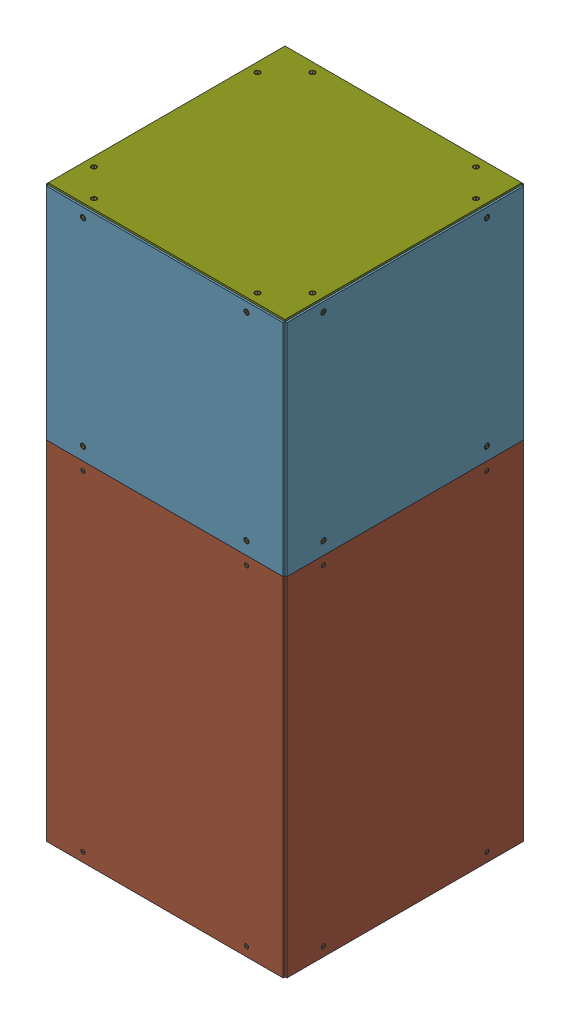
SolidWorks assembly SC.1.VIT1, configuration Showcase 570 x 570 x 870. Lengths in mm.
Overall size (656 1566.9 656).
215 component instances, 16 part files, 106 mates.
Components (placement in the parent):
- E1.CUBO-1: E1.CUBO [Estrutura 570 x 570 x 870] at (-428.8469 -414.8727 -259.3051) size (638 957.9 638)
  - E1.C-1: E1.C [E1.C1] at origin size (38 38 38)
  - E1.X-1: E1.X [E1.2] at (293.6116 -28.7561 -55.7313) x (0 1 0) z (0 0 1) size (30 570.2 30)
    - E1.X-15: E1.X [E1.2] at (43.1003 -291.3884 55.7313) size (30 570 30)
    - E1.CA-3: E1.CA [Default] at (43.7561 -291.3884 55.7313) x (0 1 0) z (0 0 1) size (14.2 10 10)
    - E1.CA-4: E1.CA [Default] at (43.7561 278.6116 55.7313) x (0 -1 0) z (0 0 1) size (14.2 10 10)
  - E1.X-10: E1.X [E1.2] at (-43.7561 70.7313 306.3884) x (1 0 0) z (0 -1 0) size (30 570.2 30)
    - E1.X-15: E1.X [E1.2] at (43.1003 -291.3884 55.7313) size (30 570 30)
    - E1.CA-3: E1.CA [Default] at (43.7561 -291.3884 55.7313) x (0 1 0) z (0 0 1) size (14.2 10 10)
    - E1.CA-4: E1.CA [Default] at (43.7561 278.6116 55.7313) x (0 -1 0) z (0 0 1) size (14.2 10 10)
  - socket button head screw_iso-2: socket button head screw_iso [ISO 7380 - M6 x 25 --- 25N] at (9.7 15 0) x (1 0 0) z (0 -0.833545 0.552452) size (28.3 10.5 10.5)
  - socket button head screw_iso-4: socket button head screw_iso [ISO 7380 - M6 x 25 --- 25N] at (0 15 9.7) x (0 0 1) z (-0.552452 -0.833545 0) size (28.3 10.5 10.5)
  - E1.C-2: E1.C [E1.C1] at (599.9999 30 -0.0001) x (1 0 0) z (0 0 -1) size (38 38 38)
  - socket button head screw_iso-5: socket button head screw_iso [ISO 7380 - M6 x 25 --- 25N] at (590.3 15 0) x (-1 0 0) z (0 0.833545 -0.552452) size (28.3 10.5 10.5)
  - E1.C-9: E1.C [E1.C1] at (0.0001 30 600.0001) x (-1 0 0) z (0 0 1) size (38 38 38)
  - socket button head screw_iso-6: socket button head screw_iso [ISO 7380 - M6 x 25 --- 25N] at (0 15 590.3) x (0 0 -1) z (0.552452 0.833545 0) size (28.3 10.5 10.5)
  - E1.PE-1: E1.PE [Default] at (9.0758 -8.3551 -4.8891) x (0.999731 0 0.023192) z (-0.023192 0 0.999731) size (24.13 30 20)
    - PÉ AJUSTÁVEL-1: PÉ AJUSTÁVEL [Default] at (-8.96 -15.5449 5.0983) size (20 30 20)
    - CLIP ROSCADO-1: CLIP ROSCADO [Default] at (-23.0861 4.4551 -0.1755) x (0.999731 0 -0.023192) z (0.023192 0 0.999731) size (19 10 11.2)
  - socket button head screw_iso-7: socket button head screw_iso [ISO 7380 - M6 x 25 --- 25N] at (590.3 15 600) x (-1 0 0) z (0 -0.833545 -0.552452) size (28.3 10.5 10.5)
  - E1.X-3: E1.X [E1.2] at (306.3884 -28.7561 655.7313) x (0 1 0) z (0 0 -1) size (30 570.2 30)
    - E1.X-15: E1.X [E1.2] at (43.1003 -291.3884 55.7313) size (30 570 30)
    - E1.CA-3: E1.CA [Default] at (43.7561 -291.3884 55.7313) x (0 1 0) z (0 0 1) size (14.2 10 10)
    - E1.CA-4: E1.CA [Default] at (43.7561 278.6116 55.7313) x (0 -1 0) z (0 0 1) size (14.2 10 10)
  - E1.X-11: E1.X [E1.2] at (643.7561 70.7313 293.6116) x (-1 0 0) z (0 -1 0) size (30 570.2 30)
    - E1.X-15: E1.X [E1.2] at (43.1003 -291.3884 55.7313) size (30 570 30)
    - E1.CA-3: E1.CA [Default] at (43.7561 -291.3884 55.7313) x (0 1 0) z (0 0 1) size (14.2 10 10)
    - E1.CA-4: E1.CA [Default] at (43.7561 278.6116 55.7313) x (0 -1 0) z (0 0 1) size (14.2 10 10)
  - E1.C-11: E1.C [E1.C1] at (600 0 600) x (-1 0 0) z (0 0 -1) size (38 38 38)
  - socket button head screw_iso-8: socket button head screw_iso [ISO 7380 - M6 x 25 --- 25N] at (600 15 9.7) x (0 0 1) z (-0.552452 0.833545 0) size (28.3 10.5 10.5)
  - socket button head screw_iso-9: socket button head screw_iso [ISO 7380 - M6 x 25 --- 25N] at (9.7 15 600) x (1 0 0) z (0 0.833545 0.552452) size (28.3 10.5 10.5)
  - socket button head screw_iso-10: socket button head screw_iso [ISO 7380 - M6 x 25 --- 25N] at (600 15 590.3) x (0 0 -1) z (0.552452 -0.833545 0) size (28.3 10.5 10.5)
  - E1.X-14: E1.X [E1.3] at (-43.7561 321.3884 -55.7313) size (30 870.2 30)
    - E1.X-15: E1.X [E1.3] at (43.1003 -291.3884 55.7313) size (30 870 30)
    - E1.CA-3: E1.CA [Default] at (43.7561 -291.3884 55.7313) x (0 1 0) z (0 0 1) size (14.2 10 10)
    - E1.CA-4: E1.CA [Default] at (43.7561 578.6116 55.7313) x (0 -1 0) z (0 0 1) size (14.2 10 10)
  - socket button head screw_iso-11: socket button head screw_iso [ISO 7380 - M6 x 25 --- 25N] at (590.3 915 600) x (-1 0 0) z (0 -0.833545 0.552452) size (28.3 10.5 10.5)
  - E1.X-6: E1.X [E1.2] at (306.3884 958.7561 544.2687) x (0 -1 0) z (0 0 1) size (30 570.2 30)
    - E1.X-15: E1.X [E1.2] at (43.1003 -291.3884 55.7313) size (30 570 30)
    - E1.CA-3: E1.CA [Default] at (43.7561 -291.3884 55.7313) x (0 1 0) z (0 0 1) size (14.2 10 10)
    - E1.CA-4: E1.CA [Default] at (43.7561 278.6116 55.7313) x (0 -1 0) z (0 0 1) size (14.2 10 10)
  - E1.X-12: E1.X [E1.2] at (643.7561 970.7313 293.6116) x (-1 0 0) z (0 -1 0) size (30 570.2 30)
    - E1.X-15: E1.X [E1.2] at (43.1003 -291.3884 55.7313) size (30 570 30)
    - E1.CA-3: E1.CA [Default] at (43.7561 -291.3884 55.7313) x (0 1 0) z (0 0 1) size (14.2 10 10)
    - E1.CA-4: E1.CA [Default] at (43.7561 278.6116 55.7313) x (0 -1 0) z (0 0 1) size (14.2 10 10)
  - E1.C-12: E1.C [E1.C1] at (599.9999 900 600.0001) size (38 38 38)
  - socket button head screw_iso-12: socket button head screw_iso [ISO 7380 - M6 x 25 --- 25N] at (600 915 9.7) x (0 0 1) z (0.552452 0.833545 0) size (28.3 10.5 10.5)
  - socket button head screw_iso-13: socket button head screw_iso [ISO 7380 - M6 x 25 --- 25N] at (9.7 915 600) x (1 0 0) z (0 0.833545 -0.552452) size (28.3 10.5 10.5)
  - socket button head screw_iso-14: socket button head screw_iso [ISO 7380 - M6 x 25 --- 25N] at (600 915 590.3) x (0 0 -1) z (-0.552452 -0.833545 0) size (28.3 10.5 10.5)
  - E1.C-10: E1.C [E1.C1] at (0 930 600) x (1 0 0) z (0 0 -1) size (38 38 38)
  - socket button head screw_iso-15: socket button head screw_iso [ISO 7380 - M6 x 25 --- 25N] at (0 915 590.3) x (0 0 -1) z (-0.552452 0.833545 0) size (28.3 10.5 10.5)
  - socket button head screw_iso-16: socket button head screw_iso [ISO 7380 - M6 x 25 --- 25N] at (0 915 9.7) x (0 0 1) z (0.552452 -0.833545 0) size (28.3 10.5 10.5)
  - socket button head screw_iso-17: socket button head screw_iso [ISO 7380 - M6 x 25 --- 25N] at (9.7 915 0) x (1 0 0) z (0 -0.833545 -0.552452) size (28.3 10.5 10.5)
  - E1.X-13: E1.X [E1.2] at (-43.7561 970.7313 306.3884) x (1 0 0) z (0 -1 0) size (30 570.2 30)
    - E1.X-15: E1.X [E1.2] at (43.1003 -291.3884 55.7313) size (30 570 30)
    - E1.CA-3: E1.CA [Default] at (43.7561 -291.3884 55.7313) x (0 1 0) z (0 0 1) size (14.2 10 10)
    - E1.CA-4: E1.CA [Default] at (43.7561 278.6116 55.7313) x (0 -1 0) z (0 0 1) size (14.2 10 10)
  - E1.X-9: E1.X [E1.2] at (293.6116 958.7561 55.7313) x (0 -1 0) z (0 0 -1) size (30 570.2 30)
    - E1.X-15: E1.X [E1.2] at (43.1003 -291.3884 55.7313) size (30 570 30)
    - E1.CA-3: E1.CA [Default] at (43.7561 -291.3884 55.7313) x (0 1 0) z (0 0 1) size (14.2 10 10)
    - E1.CA-4: E1.CA [Default] at (43.7561 278.6116 55.7313) x (0 -1 0) z (0 0 1) size (14.2 10 10)
  - E1.C-13: E1.C [E1.C1] at (0.0001 900 -0.0001) x (-1 0 0) z (0 0 -1) size (38 38 38)
  - E1.C-8: E1.C [E1.C1] at (600 930 0) x (-1 0 0) z (0 0 1) size (38 38 38)
  - socket button head screw_iso-18: socket button head screw_iso [ISO 7380 - M6 x 25 --- 25N] at (590.3 915 0) x (-1 0 0) z (0 0.833545 0.552452) size (28.3 10.5 10.5)
  - socket button head screw_iso-19: socket button head screw_iso [ISO 7380 - M6 x 25 --- 25N] at (0 24.7 0) x (0 1 0) z (-0.552452 0 0.833545) size (28.3 10.5 10.5)
  - socket button head screw_iso-20: socket button head screw_iso [ISO 7380 - M6 x 25 --- 25N] at (0 905.3 0) x (0 -1 0) z (0.981443 0 0.191756) size (28.3 10.5 10.5)
  - E1.X-16: E1.X [E1.3] at (-43.7561 321.3884 544.2687) size (30 870.2 30)
    - E1.X-15: E1.X [E1.3] at (43.1003 -291.3884 55.7313) size (30 870 30)
    - E1.CA-3: E1.CA [Default] at (43.7561 -291.3884 55.7313) x (0 1 0) z (0 0 1) size (14.2 10 10)
    - E1.CA-4: E1.CA [Default] at (43.7561 578.6116 55.7313) x (0 -1 0) z (0 0 1) size (14.2 10 10)
  - socket button head screw_iso-21: socket button head screw_iso [ISO 7380 - M6 x 25 --- 25N] at (0 905.3 600) x (0 -1 0) z (-0.981443 0 0.191756) size (28.3 10.5 10.5)
  - socket button head screw_iso-22: socket button head screw_iso [ISO 7380 - M6 x 25 --- 25N] at (0 24.7 600) x (0 1 0) z (0.552452 0 0.833545) size (28.3 10.5 10.5)
  - socket button head screw_iso-23: socket button head screw_iso [ISO 7380 - M6 x 25 --- 25N] at (600 24.7 600) x (0 1 0) z (0.552452 0 -0.833545) size (28.3 10.5 10.5)
  - socket button head screw_iso-24: socket button head screw_iso [ISO 7380 - M6 x 25 --- 25N] at (600 24.7 0) x (0 1 0) z (-0.552452 0 -0.833545) size (28.3 10.5 10.5)
  - socket button head screw_iso-25: socket button head screw_iso [ISO 7380 - M6 x 25 --- 25N] at (600 905.3 0) x (0 -1 0) z (0.981443 0 -0.191756) size (28.3 10.5 10.5)
  - E1.X-17: E1.X [E1.3] at (643.7561 321.3884 55.7313) x (-1 0 0) z (0 0 -1) size (30 870.2 30)
    - E1.X-15: E1.X [E1.3] at (43.1003 -291.3884 55.7313) size (30 870 30)
    - E1.CA-3: E1.CA [Default] at (43.7561 -291.3884 55.7313) x (0 1 0) z (0 0 1) size (14.2 10 10)
    - E1.CA-4: E1.CA [Default] at (43.7561 578.6116 55.7313) x (0 -1 0) z (0 0 1) size (14.2 10 10)
  - socket button head screw_iso-26: socket button head screw_iso [ISO 7380 - M6 x 25 --- 25N] at (600 905.3 600) x (0 -1 0) z (-0.981443 0 -0.191756) size (28.3 10.5 10.5)
  - E1.X-18: E1.X [E1.3] at (643.7561 321.3884 655.7313) x (-1 0 0) z (0 0 -1) size (30 870.2 30)
    - E1.X-15: E1.X [E1.3] at (43.1003 -291.3884 55.7313) size (30 870 30)
    - E1.CA-3: E1.CA [Default] at (43.7561 -291.3884 55.7313) x (0 1 0) z (0 0 1) size (14.2 10 10)
    - E1.CA-4: E1.CA [Default] at (43.7561 578.6116 55.7313) x (0 -1 0) z (0 0 1) size (14.2 10 10)
  - E1.PE-3: E1.PE [Default] at (590.9241 -8.3551 4.889) x (-0.999731 0 -0.023192) z (0.023192 0 -0.999731) size (24.13 30 20)
    - PÉ AJUSTÁVEL-1: PÉ AJUSTÁVEL [Default] at (-8.96 -15.5449 5.0983) size (20 30 20)
    - CLIP ROSCADO-1: CLIP ROSCADO [Default] at (-23.0861 4.4551 -0.1755) x (0.999731 0 -0.023192) z (0.023192 0 0.999731) size (19 10 11.2)
  - E1.PE-4: E1.PE [Default] at (590.9242 -8.3551 604.8891) x (-0.999731 0 -0.023192) z (0.023192 0 -0.999731) size (24.13 30 20)
    - PÉ AJUSTÁVEL-1: PÉ AJUSTÁVEL [Default] at (-8.96 -15.5449 5.0983) size (20 30 20)
    - CLIP ROSCADO-1: CLIP ROSCADO [Default] at (-23.0861 4.4551 -0.1755) x (0.999731 0 -0.023192) z (0.023192 0 0.999731) size (19 10 11.2)
  - E1.PE-5: E1.PE [Default] at (9.0759 -8.3551 595.111) x (0.999731 0 0.023192) z (-0.023192 0 0.999731) size (24.13 30 20)
    - PÉ AJUSTÁVEL-1: PÉ AJUSTÁVEL [Default] at (-8.96 -15.5449 5.0983) size (20 30 20)
    - CLIP ROSCADO-1: CLIP ROSCADO [Default] at (-23.0861 4.4551 -0.1755) x (0.999731 0 -0.023192) z (0.023192 0 0.999731) size (19 10 11.2)
- SC.1.G-1: SC.1.G [Default] at (-446.8469 500.1273 -182.3051) x (0 0 1) z (-1 0 0) size (70 79.5 2)
- SC.1.G-10: SC.1.G [Default] at (-446.8469 500.1273 263.6949) x (0 0 1) z (-1 0 0) size (70 79.5 2)
- E1.EP-1: E1.EP [Default] at (-448.8469 500.1273 263.6949) x (0 0.966847 0.255355) z (0 0.255355 -0.966847) size (10 5 10)
- E1.EP-9: E1.EP [Default] at (-448.8469 500.1273 -182.3051) x (0 0.966847 0.255355) z (0 0.255355 -0.966847) size (10 5 10)
- SC.1.G-12: SC.1.G [Default] at (94.1531 500.1273 -277.3051) x (-1 0 0) z (0 0 -1) size (70 79.5 2)
- E1.EP-11: E1.EP [Default] at (-351.8469 500.1273 -279.3051) x (-0.255355 0.966847 0) z (0.966847 0.255355 0) size (10 5 10)
- SC.1.G-14: SC.1.G [Default] at (-351.8469 500.1273 -277.3051) x (-1 0 0) z (0 0 -1) size (70 79.5 2)
- E1.EP-13: E1.EP [Default] at (94.1531 500.1273 -279.3051) x (-0.255355 0.966847 0) z (0.966847 0.255355 0) size (10 5 10)
- E1.EP-14: E1.EP [Default] at (94.1531 500.1273 360.6949) x (-0.255355 0.966847 0) z (-0.966847 -0.255355 0) size (10 5 10)
- SC.1.G-15: SC.1.G [Default] at (-351.8469 500.1273 356.6949) x (-1 0 0) z (0 0 -1) size (70 79.5 2)
- E1.EP-12: E1.EP [Default] at (-351.8469 500.1273 360.6949) x (-0.255355 0.966847 0) z (-0.966847 -0.255355 0) size (10 5 10)
- SC.1.G-13: SC.1.G [Default] at (94.1531 500.1273 356.6949) x (-1 0 0) z (0 0 -1) size (70 79.5 2)
- E1.EP-10: E1.EP [Default] at (191.1531 500.1273 -182.3051) x (0 0.966847 0.255355) z (0 -0.255355 0.966847) size (10 5 10)
- SC.1.G-11: SC.1.G [Default] at (187.1531 500.1273 263.6949) x (0 0 1) z (-1 0 0) size (70 79.5 2)
- SC.1.G-9: SC.1.G [Default] at (187.1531 500.1273 -182.3051) x (0 0 1) z (-1 0 0) size (70 79.5 2)
- E1.EP-8: E1.EP [Default] at (191.1531 500.1273 263.6949) x (0 0.966847 0.255355) z (0 -0.255355 0.966847) size (10 5 10)
- SC.1.AC2-1: SC.1.AC2 [Default] at (-451.8469 558.1273 -182.3051) size (10 13 13)
- SC.1.AC1-1: SC.1.AC1 [Default] at (-451.8469 558.1273 -182.3051) x (1 0 0) z (0 -0.384516 0.923118) size (5 13 13)
- SC.1.AC1-11: SC.1.AC1 [Default] at (94.1531 558.1273 -282.3051) x (0 0 1) z (-0.41724 -0.908796 0) size (5 13 13)
- SC.1.AC2-11: SC.1.AC2 [Default] at (94.1531 558.1273 -282.3051) x (0 0 1) z (-1 0 0) size (10 13 13)
- SC.1.AC2-13: SC.1.AC2 [Default] at (-451.8469 558.1273 263.6949) size (10 13 13)
- SC.1.AC1-13: SC.1.AC1 [Default] at (-451.8469 558.1273 263.6949) x (1 0 0) z (0 -0.384516 0.923118) size (5 13 13)
- SC.1.AC2-15: SC.1.AC2 [Default] at (-351.8469 558.1273 -282.3051) x (0 0 1) z (-1 0 0) size (10 13 13)
- SC.1.AC1-15: SC.1.AC1 [Default] at (-351.8469 558.1273 -282.3051) x (0 0 1) z (-0.923118 -0.384516 0) size (5 13 13)
- SC.1.AC2-16: SC.1.AC2 [Default] at (-351.8469 558.1273 363.6949) x (0 0 -1) z (1 0 0) size (10 13 13)
- SC.1.AC1-16: SC.1.AC1 [Default] at (-351.8469 558.1273 363.6949) x (0 0 -1) z (0.923118 0.384516 0) size (5 13 13)
- SC.1.AC2-12: SC.1.AC2 [Default] at (94.1531 558.1273 363.6949) x (0 0 -1) z (1 0 0) size (10 13 13)
- SC.1.AC1-12: SC.1.AC1 [Default] at (94.1531 558.1273 363.6949) x (0 0 -1) z (0.41724 0.908796 0) size (5 13 13)
- SC.1.AC2-10: SC.1.AC2 [Default] at (194.1531 558.1273 -182.3051) x (-1 0 0) z (0 0 -1) size (10 13 13)
- SC.1.AC1-10: SC.1.AC1 [Default] at (194.1531 558.1273 -182.3051) x (-1 0 0) z (0 0.384516 -0.923118) size (5 13 13)
- SC.1.AC2-14: SC.1.AC2 [Default] at (194.1531 558.1273 263.6949) x (-1 0 0) z (0 0 -1) size (10 13 13)
- SC.1.AC1-14: SC.1.AC1 [Default] at (194.1531 558.1273 263.6949) x (-1 0 0) z (0 0.384516 -0.923118) size (5 13 13)
- SC.1.RL-1: SC.1.RL [Lateral 953 x 646] at (-448.8469 51.6273 40.6949) x (0 0 1) z (-1 0 0) size (646 953 8)
- SC.1.RL-6: SC.1.RL [Lateral 953 x 646] at (-128.8469 51.6273 -279.3051) x (-1 0 0) z (0 0 -1) size (646 953 8)
- socket countersunk head screw_iso-1: socket countersunk head screw_iso [ISO 10642 - M5 x 12 --- 12N] at (-456.8469 500.1273 263.6949) size (12 9.43 9.43)
- socket countersunk head screw_iso-3: socket countersunk head screw_iso [ISO 10642 - M5 x 12 --- 12N] at (-456.8469 500.1273 -182.3051) size (12 9.43 9.43)
- socket countersunk head screw_iso-4: socket countersunk head screw_iso [ISO 10642 - M5 x 12 --- 12N] at (-456.8469 -399.8727 -182.3051) size (12 9.43 9.43)
- socket countersunk head screw_iso-5: socket countersunk head screw_iso [ISO 10642 - M5 x 12 --- 12N] at (-456.8469 -399.8727 263.6949) size (12 9.43 9.43)
- socket countersunk head screw_iso-6: socket countersunk head screw_iso [ISO 10642 - M5 x 12 --- 12N] at (-351.8469 -399.8727 -287.3051) x (0 0 1) z (-1 0 0) size (12 9.43 9.43)
- socket countersunk head screw_iso-7: socket countersunk head screw_iso [ISO 10642 - M5 x 12 --- 12N] at (94.1531 -399.8727 -287.3051) x (0 0 1) z (-1 0 0) size (12 9.43 9.43)
- socket countersunk head screw_iso-8: socket countersunk head screw_iso [ISO 10642 - M5 x 12 --- 12N] at (94.1531 500.1273 -287.3051) x (0 0 1) z (-1 0 0) size (12 9.43 9.43)
- socket countersunk head screw_iso-9: socket countersunk head screw_iso [ISO 10642 - M5 x 12 --- 12N] at (-351.8469 500.1273 -287.3051) x (0 0 1) z (-1 0 0) size (12 9.43 9.43)
- socket countersunk head screw_iso-10: socket countersunk head screw_iso [ISO 10642 - M5 x 16 --- 16N] at (-351.8469 558.1273 -287.3051) x (0 0 1) z (-1 0 0) size (16 9.43 9.43)
- socket countersunk head screw_iso-11: socket countersunk head screw_iso [ISO 10642 - M5 x 16 --- 16N] at (94.1531 558.1273 -287.3051) x (0 0 1) z (-1 0 0) size (16 9.43 9.43)
- socket countersunk head screw_iso-12: socket countersunk head screw_iso [ISO 10642 - M5 x 16 --- 16N] at (-456.8469 558.1273 -182.3051) size (16 9.43 9.43)
- socket countersunk head screw_iso-13: socket countersunk head screw_iso [ISO 10642 - M5 x 16 --- 16N] at (-456.8469 558.1273 263.6949) size (16 9.43 9.43)
- socket countersunk head screw_iso-14: socket countersunk head screw_iso [ISO 10642 - M5 x 16 --- 16N] at (-351.8469 558.1273 368.6949) x (0 0 -1) z (1 0 0) size (16 9.43 9.43)
- socket countersunk head screw_iso-15: socket countersunk head screw_iso [ISO 10642 - M5 x 16 --- 16N] at (94.1531 558.1273 368.6949) x (0 0 -1) z (1 0 0) size (16 9.43 9.43)
- SC.1.RL-7: SC.1.RL [Lateral 953 x 646] at (-128.8469 51.6273 360.6949) size (646 953 8)
- socket countersunk head screw_iso-16: socket countersunk head screw_iso [ISO 10642 - M5 x 12 --- 12N] at (94.1531 500.1273 368.6949) x (0 0 -1) z (1 0 0) size (12 9.43 9.43)
- socket countersunk head screw_iso-17: socket countersunk head screw_iso [ISO 10642 - M5 x 12 --- 12N] at (-351.8469 500.1273 368.6949) x (0 0 -1) z (1 0 0) size (12 9.43 9.43)
- socket countersunk head screw_iso-18: socket countersunk head screw_iso [ISO 10642 - M5 x 12 --- 12N] at (-351.8469 -399.8727 368.6949) x (0 0 -1) z (1 0 0) size (12 9.43 9.43)
- socket countersunk head screw_iso-19: socket countersunk head screw_iso [ISO 10642 - M5 x 12 --- 12N] at (94.1531 -399.8727 368.6949) x (0 0 -1) z (1 0 0) size (12 9.43 9.43)
- socket countersunk head screw_iso-20: socket countersunk head screw_iso [ISO 10642 - M5 x 16 --- 16N] at (199.1531 558.1273 -182.3051) x (-1 0 0) z (0 0 -1) size (16 9.43 9.43)
- socket countersunk head screw_iso-21: socket countersunk head screw_iso [ISO 10642 - M5 x 12 --- 12N] at (199.1531 500.1273 -182.3051) x (-1 0 0) z (0 0 -1) size (12 9.43 9.43)
- SC.1.RL-5: SC.1.RL [Lateral 953 x 646] at (191.1531 51.6273 40.6949) x (0 0 -1) z (1 0 0) size (646 953 8)
- socket countersunk head screw_iso-22: socket countersunk head screw_iso [ISO 10642 - M5 x 16 --- 16N] at (199.1531 558.1273 263.6949) x (-1 0 0) z (0 0 -1) size (16 9.43 9.43)
- socket countersunk head screw_iso-23: socket countersunk head screw_iso [ISO 10642 - M5 x 12 --- 12N] at (199.1531 500.1273 263.6949) x (-1 0 0) z (0 0 -1) size (12 9.43 9.43)
- socket countersunk head screw_iso-24: socket countersunk head screw_iso [ISO 10642 - M5 x 12 --- 12N] at (199.1531 -399.8727 263.6949) x (-1 0 0) z (0 0 -1) size (12 9.43 9.43)
- socket countersunk head screw_iso-25: socket countersunk head screw_iso [ISO 10642 - M5 x 12 --- 12N] at (199.1531 -399.8727 -182.3051) x (-1 0 0) z (0 0 -1) size (12 9.43 9.43)
- SC.1.RT-1: SC.1.RT [Topo 639 x 639] at (-128.8469 520.1273 40.6949) size (639 8 639)
- SC.1.VL-1: SC.1.VL [Lateral 646 x 600] at (-451.8469 823.1273 40.6949) x (0 0 1) z (-1 0 0) size (646 600 5)
- SC.1.VL-4: SC.1.VL [Lateral 646 x 600] at (-128.8469 823.1273 -282.3051) x (-1 0 0) z (0 0 -1) size (646 600 5)
- SC.1.L-1: SC.1.L [Default] at (-433.5969 1104.8773 -188.8051) size (26.5 26.5 13)
- SC.1.AC2-17: SC.1.AC2 [Default] at (-451.8469 1098.1273 -182.3051) size (10 13 13)
- SC.1.AC1-17: SC.1.AC1 [Default] at (-451.8469 1098.1273 -182.3051) size (5 13 13)
- SC.1.AC2-23: SC.1.AC2 [Default] at (-426.8469 1123.1273 -182.3051) x (0 -1 0) z (0 0 1) size (10 13 13)
- SC.1.AC1-24: SC.1.AC1 [Default] at (-426.8469 1123.1273 -182.3051) x (0 -1 0) z (0 0 1) size (5 13 13)
- socket countersunk head screw_iso-26: socket countersunk head screw_iso [ISO 10642 - M5 x 16 --- 16N] at (-456.8469 1098.1273 -182.3051) size (16 9.43 9.43)
- socket countersunk head screw_iso-27: socket countersunk head screw_iso [ISO 10642 - M5 x 16 --- 16N] at (-426.8469 1128.1273 -182.3051) x (0 -1 0) z (0 0 1) size (16 9.43 9.43)
- SC.1.L-2: SC.1.L [Default] at (-433.5969 1104.8773 257.1949) size (26.5 26.5 13)
- SC.1.AC2-18: SC.1.AC2 [Default] at (-451.8469 1098.1273 263.6949) size (10 13 13)
- SC.1.AC1-18: SC.1.AC1 [Default] at (-451.8469 1098.1273 263.6949) size (5 13 13)
- SC.1.AC2-24: SC.1.AC2 [Default] at (-426.8469 1123.1273 263.6949) x (0 -1 0) z (0 0 1) size (10 13 13)
- SC.1.AC1-25: SC.1.AC1 [Default] at (-426.8469 1123.1273 263.6949) x (0 -1 0) z (0 0 1) size (5 13 13)
- socket countersunk head screw_iso-28: socket countersunk head screw_iso [ISO 10642 - M5 x 16 --- 16N] at (-456.8469 1098.1273 263.6949) size (16 9.43 9.43)
- socket countersunk head screw_iso-29: socket countersunk head screw_iso [ISO 10642 - M5 x 16 --- 16N] at (-426.8469 1128.1273 263.6949) x (0 -1 0) z (0 0 1) size (16 9.43 9.43)
- SC.1.L-7: SC.1.L [Default] at (-345.3469 1104.8773 -264.0551) x (0 0 1) z (-1 0 0) size (26.5 26.5 13)
- SC.1.AC2-27: SC.1.AC2 [Default] at (-351.8469 1098.1273 -282.3051) x (0 0 1) z (-1 0 0) size (10 13 13)
- SC.1.AC2-31: SC.1.AC2 [Default] at (-351.8469 1123.1273 -257.3051) x (0 -1 0) z (0 0 1) size (10 13 13)
- SC.1.AC1-28: SC.1.AC1 [Default] at (-351.8469 1123.1273 -257.3051) x (0 -1 0) z (0 0 1) size (5 13 13)
- socket countersunk head screw_iso-30: socket countersunk head screw_iso [ISO 10642 - M5 x 16 --- 16N] at (-351.8469 1098.1273 -287.3051) x (0 0 1) z (-1 0 0) size (16 9.43 9.43)
- socket countersunk head screw_iso-31: socket countersunk head screw_iso [ISO 10642 - M5 x 16 --- 16N] at (-351.8469 1128.1273 -257.3051) x (0 -1 0) z (0 0 1) size (16 9.43 9.43)
- SC.1.AC1-32: SC.1.AC1 [Default] at (-351.8469 1098.1273 -282.3051) x (0 0 1) z (-1 0 0) size (5 13 13)
- socket countersunk head screw_iso-32: socket countersunk head screw_iso [ISO 10642 - M5 x 16 --- 16N] at (94.1531 1128.1273 -257.3051) x (0 -1 0) z (0 0 -1) size (16 9.43 9.43)
- SC.1.AC1-29: SC.1.AC1 [Default] at (94.1531 1123.1273 -257.3051) x (0 -1 0) z (0 0 -1) size (5 13 13)
- SC.1.AC2-32: SC.1.AC2 [Default] at (94.1531 1123.1273 -257.3051) x (0 -1 0) z (0 0 -1) size (10 13 13)
- SC.1.L-8: SC.1.L [Default] at (100.6531 1104.8773 -264.0551) x (0 0 1) z (-1 0 0) size (26.5 26.5 13)
- SC.1.AC2-28: SC.1.AC2 [Default] at (94.1531 1098.1273 -282.3051) x (0 0 1) z (-1 0 0) size (10 13 13)
- socket countersunk head screw_iso-33: socket countersunk head screw_iso [ISO 10642 - M5 x 16 --- 16N] at (94.1531 1098.1273 -287.3051) x (0 0 1) z (-1 0 0) size (16 9.43 9.43)
- SC.1.AC1-33: SC.1.AC1 [Default] at (94.1531 1098.1273 -282.3051) x (0 0 1) z (-1 0 0) size (5 13 13)
- SC.1.AC1-21: SC.1.AC1 [Default] at (194.1531 1098.1273 263.6949) x (-1 0 0) z (0 0 -1) size (5 13 13)
- SC.1.AC2-25: SC.1.AC2 [Default] at (169.1531 1123.1273 263.6949) x (0 -1 0) z (0 0 -1) size (10 13 13)
- SC.1.L-5: SC.1.L [Default] at (175.9031 1104.8773 270.1949) x (-1 0 0) z (0 0 -1) size (26.5 26.5 13)
- socket countersunk head screw_iso-34: socket countersunk head screw_iso [ISO 10642 - M5 x 16 --- 16N] at (169.1531 1128.1273 263.6949) x (0 -1 0) z (0 0 -1) size (16 9.43 9.43)
- SC.1.AC2-21: SC.1.AC2 [Default] at (194.1531 1098.1273 263.6949) x (-1 0 0) z (0 0 -1) size (10 13 13)
- SC.1.AC1-26: SC.1.AC1 [Default] at (169.1531 1123.1273 263.6949) x (0 -1 0) z (0 0 -1) size (5 13 13)
- socket countersunk head screw_iso-35: socket countersunk head screw_iso [ISO 10642 - M5 x 16 --- 16N] at (199.1531 1098.1273 263.6949) x (-1 0 0) z (0 0 -1) size (16 9.43 9.43)
- SC.1.VL-3: SC.1.VL [Lateral 646 x 600] at (194.1531 823.1273 40.6949) x (0 0 -1) z (1 0 0) size (646 600 5)
- socket countersunk head screw_iso-36: socket countersunk head screw_iso [ISO 10642 - M5 x 16 --- 16N] at (169.1531 1128.1273 -182.3051) x (0 -1 0) z (0 0 -1) size (16 9.43 9.43)
- socket countersunk head screw_iso-37: socket countersunk head screw_iso [ISO 10642 - M5 x 16 --- 16N] at (199.1531 1098.1273 -182.3051) x (-1 0 0) z (0 0 -1) size (16 9.43 9.43)
- SC.1.AC1-23: SC.1.AC1 [Default] at (194.1531 1098.1273 -182.3051) x (-1 0 0) z (0 0 -1) size (5 13 13)
- SC.1.AC2-22: SC.1.AC2 [Default] at (194.1531 1098.1273 -182.3051) x (-1 0 0) z (0 0 -1) size (10 13 13)
- SC.1.L-6: SC.1.L [Default] at (175.9031 1104.8773 -175.8051) x (-1 0 0) z (0 0 -1) size (26.5 26.5 13)
- SC.1.AC1-27: SC.1.AC1 [Default] at (169.1531 1123.1273 -182.3051) x (0 -1 0) z (0 0 -1) size (5 13 13)
- SC.1.AC2-26: SC.1.AC2 [Default] at (169.1531 1123.1273 -182.3051) x (0 -1 0) z (0 0 -1) size (10 13 13)
- SC.1.AC1-30: SC.1.AC1 [Default] at (94.1531 1123.1273 338.6949) x (0 -1 0) z (0 0 -1) size (5 13 13)
- socket countersunk head screw_iso-38: socket countersunk head screw_iso [ISO 10642 - M5 x 16 --- 16N] at (-351.8469 1098.1273 368.6949) x (0 0 -1) z (1 0 0) size (16 9.43 9.43)
- SC.1.L-10: SC.1.L [Default] at (-358.3469 1104.8773 345.4449) x (0 0 -1) z (1 0 0) size (26.5 26.5 13)
- SC.1.AC2-30: SC.1.AC2 [Default] at (-351.8469 1098.1273 363.6949) x (0 0 -1) z (1 0 0) size (10 13 13)
- SC.1.AC1-34: SC.1.AC1 [Default] at (94.1531 1098.1273 363.6949) x (0 0 -1) z (1 0 0) size (5 13 13)
- SC.1.AC2-34: SC.1.AC2 [Default] at (-351.8469 1123.1273 338.6949) x (0 -1 0) z (0 0 1) size (10 13 13)
- SC.1.AC2-33: SC.1.AC2 [Default] at (94.1531 1123.1273 338.6949) x (0 -1 0) z (0 0 -1) size (10 13 13)
- SC.1.L-9: SC.1.L [Default] at (87.6531 1104.8773 345.4449) x (0 0 -1) z (1 0 0) size (26.5 26.5 13)
- SC.1.AC2-29: SC.1.AC2 [Default] at (94.1531 1098.1273 363.6949) x (0 0 -1) z (1 0 0) size (10 13 13)
- socket countersunk head screw_iso-39: socket countersunk head screw_iso [ISO 10642 - M5 x 16 --- 16N] at (94.1531 1128.1273 338.6949) x (0 -1 0) z (0 0 -1) size (16 9.43 9.43)
- SC.1.AC1-31: SC.1.AC1 [Default] at (-351.8469 1123.1273 338.6949) x (0 -1 0) z (0 0 1) size (5 13 13)
- socket countersunk head screw_iso-40: socket countersunk head screw_iso [ISO 10642 - M5 x 16 --- 16N] at (-351.8469 1128.1273 338.6949) x (0 -1 0) z (0 0 1) size (16 9.43 9.43)
- SC.1.AC1-35: SC.1.AC1 [Default] at (-351.8469 1098.1273 363.6949) x (0 0 -1) z (1 0 0) size (5 13 13)
- socket countersunk head screw_iso-41: socket countersunk head screw_iso [ISO 10642 - M5 x 16 --- 16N] at (94.1531 1098.1273 368.6949) x (0 0 -1) z (1 0 0) size (16 9.43 9.43)
- SC.1.VL-5: SC.1.VL [Lateral 646 x 600] at (-128.8469 823.1273 363.6949) size (646 600 5)
- SC.1.VT-1: SC.1.VT [Topo 646 x 646] at (-128.8469 1123.1273 40.6949) x (0 0 1) z (-1 0 0) size (646 5 646)
Mates (geometry in assembly coordinates):
- Distance1: distance = 1 mm anti-aligned: plane of SC.1.G-1 through (-444.8469 558.1273 -182.3051) normal (1 0 0); plane of E1.CUBO-1/E1.X-10/E1.X-15 through (-443.8469 -411.8727 325.6949) normal (-1 0 0)
- Coincident2: coincident anti-aligned: plane of E1.CUBO-1/E1.X-14/E1.X-15 through (-433.1469 485.1273 -274.1051) normal (0 1 0); plane of SC.1.G-1 through (-444.8469 485.1273 -212.3051) normal (0 -1 0)
- Distance2: distance = 27 mm aligned: plane of SC.1.G-1 through (-444.8469 515.1273 -217.3051) normal (0 0 -1); plane of E1.CUBO-1/E1.X-10/E1.X-15 through (-433.1469 -385.0727 -244.3051) normal (0 0 -1)
- Distance6: distance = 1 mm anti-aligned: plane of SC.1.G-10 through (-444.8469 558.1273 263.6949) normal (1 0 0); plane of E1.CUBO-1/E1.X-10/E1.X-15 through (-443.8469 -387.8727 325.6949) normal (-1 0 0)
- Coincident6: coincident anti-aligned: plane of E1.CUBO-1/E1.X-14/E1.X-15 through (-433.1469 485.1273 -274.1051) normal (0 1 0); plane of SC.1.G-10 through (-444.8469 485.1273 233.6949) normal (0 -1 0)
- Distance7: distance = 27 mm aligned: plane of SC.1.G-10 through (-444.8469 490.1273 298.6949) normal (0 0 1); plane of E1.CUBO-1/E1.X-10/E1.X-15 through (-433.1469 -385.0727 325.6949) normal (0 0 1)
- Coincident8: coincident anti-aligned: plane of E1.CUBO-1/E1.X-10/E1.X-15 through (-443.8469 -387.8727 325.6949) normal (-1 0 0); plane of E1.EP-1 through (-443.8469 500.1273 263.6949) normal (1 0 0)
- Concentric1: concentric aligned: cylinder of SC.1.G-10 through (-444.8469 500.1273 263.6949) axis (-1 0 0) radius 5.1; cylinder of E1.EP-1 through (-443.8469 500.1273 263.6949) axis (-1 0 0) radius 5
- Coincident9: coincident anti-aligned: plane of E1.CUBO-1/E1.X-10/E1.X-15 through (-443.8469 -387.8727 325.6949) normal (-1 0 0); plane of E1.EP-9 through (-443.8469 500.1273 -182.3051) normal (1 0 0)
- Concentric2: concentric aligned: cylinder of SC.1.G-1 through (-444.8469 500.1273 -182.3051) axis (-1 0 0) radius 5.1; cylinder of E1.EP-9 through (-443.8469 500.1273 -182.3051) axis (-1 0 0) radius 5
- Distance8: distance = 1 mm anti-aligned: plane of SC.1.G-12 through (94.1531 558.1273 -275.3051) normal (0 0 1); plane of E1.CUBO-1/E1.X-1/E1.X-15 through (-413.8469 -387.8727 -274.3051) normal (0 0 -1)
- Coincident10: coincident anti-aligned: plane of E1.CUBO-1/E1.X-14/E1.X-15 through (-433.1469 485.1273 -274.1051) normal (0 1 0); plane of SC.1.G-12 through (124.1531 485.1273 -275.3051) normal (0 -1 0)
- Distance9: distance = 27 mm aligned: plane of SC.1.G-12 through (129.1531 515.1273 -275.3051) normal (1 0 0); plane of E1.CUBO-1/E1.X-1/E1.X-15 through (156.1531 -404.1727 -274.1051) normal (1 0 0)
- Concentric6: concentric aligned: cylinder of E1.EP-11 through (-351.8469 500.1273 -274.3051) axis (0 0 -1) radius 5; cylinder of SC.1.G-14 through (-351.8469 500.1273 -275.3051) axis (0 0 -1) radius 5.1
- Distance10: distance = 1 mm anti-aligned: plane of SC.1.G-14 through (-351.8469 558.1273 -275.3051) normal (0 0 1); plane of E1.CUBO-1/E1.X-1/E1.X-15 through (-413.8469 -387.8727 -274.3051) normal (0 0 -1)
- Coincident11: coincident anti-aligned: plane of E1.CUBO-1/E1.X-14/E1.X-15 through (-433.1469 485.1273 -274.1051) normal (0 1 0); plane of SC.1.G-14 through (-321.8469 485.1273 -275.3051) normal (0 -1 0)
- Distance11: distance = 27 mm aligned: plane of SC.1.G-14 through (-386.8469 490.1273 -275.3051) normal (-1 0 0); plane of E1.CUBO-1/E1.X-1/E1.X-15 through (-413.8469 -404.1727 -274.1051) normal (-1 0 0)
- Coincident14: coincident anti-aligned: plane of E1.CUBO-1/E1.X-1/E1.X-15 through (-413.8469 -387.8727 -274.3051) normal (0 0 -1); plane of E1.EP-11 through (-351.8469 500.1273 -274.3051) normal (0 0 1)
- Coincident15: coincident anti-aligned: plane of E1.CUBO-1/E1.X-1/E1.X-15 through (-413.8469 -387.8727 -274.3051) normal (0 0 -1); plane of E1.EP-13 through (94.1531 500.1273 -274.3051) normal (0 0 1)
- Concentric7: concentric aligned: cylinder of SC.1.G-12 through (94.1531 500.1273 -275.3051) axis (0 0 -1) radius 5.1; cylinder of E1.EP-13 through (94.1531 500.1273 -274.3051) axis (0 0 -1) radius 5
- Concentric8: concentric aligned: cylinder of SC.1.G-1 through (-446.8469 558.1273 -182.3051) axis (-1 0 0) radius 2.1; cylinder of SC.1.AC2-1 through (-461.4266 558.1273 -182.3051) axis (-1 0 0) radius 4
- Coincident16: coincident anti-aligned: plane of SC.1.G-1 through (-446.8469 558.1273 -182.3051) normal (-1 0 0); plane of SC.1.AC2-1 through (-446.8469 562.1273 -182.3051) normal (1 0 0)
- Concentric9: concentric aligned: cylinder of SC.1.AC2-1 through (-461.4266 558.1273 -182.3051) axis (-1 0 0) radius 4; cylinder of SC.1.AC1-1 through (-446.8469 558.1273 -182.3051) axis (-1 0 0) radius 4
- Coincident17: coincident anti-aligned: plane of SC.1.G-1 through (-446.8469 558.1273 -182.3051) normal (-1 0 0); plane of SC.1.AC1-1 through (-446.8469 558.1273 -182.3051) normal (1 0 0)
- Concentric14: concentric aligned: cylinder of SC.1.AC1-11 through (94.1531 558.1273 -277.3051) axis (0 0 -1) radius 4; cylinder of SC.1.AC2-11 through (94.1531 558.1273 -291.8847) axis (0 0 -1) radius 4
- Concentric15: concentric aligned: cylinder of SC.1.G-12 through (94.1531 558.1273 -277.3051) axis (0 0 -1) radius 2.1; cylinder of SC.1.AC2-11 through (94.1531 558.1273 -291.8847) axis (0 0 -1) radius 4
- Coincident23: coincident anti-aligned: plane of SC.1.G-12 through (94.1531 558.1273 -277.3051) normal (0 0 -1); plane of SC.1.AC2-11 through (94.1531 562.1273 -277.3051) normal (0 0 1)
- Coincident26: coincident anti-aligned: plane of SC.1.G-12 through (94.1531 558.1273 -277.3051) normal (0 0 -1); plane of SC.1.AC1-11 through (94.1531 558.1273 -277.3051) normal (0 0 1)
- Concentric18: concentric aligned: cylinder of SC.1.AC2-13 through (-461.4266 558.1273 263.6949) axis (-1 0 0) radius 4; cylinder of SC.1.AC1-13 through (-446.8469 558.1273 263.6949) axis (-1 0 0) radius 4
- Concentric19: concentric aligned: cylinder of SC.1.G-10 through (-446.8469 558.1273 263.6949) axis (-1 0 0) radius 2.1; cylinder of SC.1.AC2-13 through (-461.4266 558.1273 263.6949) axis (-1 0 0) radius 4
- Coincident27: coincident anti-aligned: plane of SC.1.G-10 through (-446.8469 558.1273 263.6949) normal (-1 0 0); plane of SC.1.AC2-13 through (-446.8469 562.1273 263.6949) normal (1 0 0)
- Coincident28: coincident anti-aligned: plane of SC.1.G-10 through (-446.8469 558.1273 263.6949) normal (-1 0 0); plane of SC.1.AC1-13 through (-446.8469 558.1273 263.6949) normal (1 0 0)
- Concentric20: concentric aligned: cylinder of SC.1.AC2-15 through (-351.8469 558.1273 -291.8847) axis (0 0 -1) radius 4; cylinder of SC.1.AC1-15 through (-351.8469 558.1273 -277.3051) axis (0 0 -1) radius 4
- Concentric21: concentric aligned: cylinder of SC.1.G-14 through (-351.8469 558.1273 -277.3051) axis (0 0 -1) radius 2.1; cylinder of SC.1.AC2-15 through (-351.8469 558.1273 -291.8847) axis (0 0 -1) radius 4
- Coincident29: coincident anti-aligned: plane of SC.1.G-14 through (-351.8469 558.1273 -277.3051) normal (0 0 -1); plane of SC.1.AC2-15 through (-351.8469 562.1273 -277.3051) normal (0 0 1)
- Coincident30: coincident anti-aligned: plane of SC.1.G-14 through (-351.8469 558.1273 -277.3051) normal (0 0 -1); plane of SC.1.AC1-15 through (-351.8469 558.1273 -277.3051) normal (0 0 1)
- Coincident31: coincident anti-aligned: plane of E1.EP-9 through (-448.8469 500.1273 -182.3051) normal (-1 0 0); plane of SC.1.RL-1 through (-448.8469 51.6273 40.6949) normal (1 0 0)
- Distance12: distance = 8 mm aligned: plane of SC.1.RL-1 through (-456.8469 -424.8727 -282.3051) normal (0 0 -1); plane of E1.CUBO-1/E1.X-14/E1.X-15 through (-440.8469 485.1273 -274.3051) normal (0 0 -1)
- Distance15: distance = 10 mm aligned: plane of E1.CUBO-1/E1.X-10/E1.X-15 through (-440.8469 -414.8727 325.6949) normal (0 -1 0); plane of SC.1.RL-1 through (-456.8469 -424.8727 -282.3051) normal (0 -1 0)
- Coincident34: coincident anti-aligned: plane of E1.EP-13 through (94.1531 500.1273 -279.3051) normal (0 0 -1); plane of SC.1.RL-6 through (-128.8469 51.6273 -279.3051) normal (0 0 1)
- Distance13: distance = 8 mm aligned: plane of SC.1.RL-6 through (-451.8469 -424.8727 -287.3051) normal (-1 0 0); plane of E1.CUBO-1/E1.X-10/E1.X-15 through (-443.8469 -387.8727 325.6949) normal (-1 0 0)
- Distance14: distance = 10 mm aligned: plane of SC.1.RL-6 through (194.1531 -424.8727 -287.3051) normal (0 -1 0); plane of E1.CUBO-1/E1.X-1/E1.X-15 through (-413.8469 -414.8727 -271.3051) normal (0 -1 0)
- Concentric23: concentric aligned: cylinder of SC.1.RL-1 through (-448.8469 500.1273 263.6949) axis (-1 0 0) radius 2.5; cylinder of socket countersunk head screw_iso-1 through (-456.8469 500.1273 263.6949) axis (-1 0 0) radius 2.5
- Coincident37: coincident aligned: plane of SC.1.RL-1 through (-456.8469 51.6273 40.6949) normal (-1 0 0); plane of socket countersunk head screw_iso-1 through (-456.8469 500.1273 263.6949) normal (-1 0 0)
- Concentric24: concentric aligned: cylinder of SC.1.RL-1 through (-448.8469 500.1273 -182.3051) axis (-1 0 0) radius 2.5; cylinder of socket countersunk head screw_iso-3 through (-456.8469 500.1273 -182.3051) axis (-1 0 0) radius 2.5
- Coincident38: coincident aligned: plane of SC.1.RL-1 through (-456.8469 51.6273 40.6949) normal (-1 0 0); plane of socket countersunk head screw_iso-3 through (-456.8469 500.1273 -182.3051) normal (-1 0 0)
- Concentric25: concentric aligned: cylinder of SC.1.RL-1 through (-448.8469 -399.8727 -182.3051) axis (-1 0 0) radius 2.5; cylinder of socket countersunk head screw_iso-4 through (-456.8469 -399.8727 -182.3051) axis (-1 0 0) radius 2.5
- Coincident39: coincident aligned: plane of SC.1.RL-1 through (-456.8469 51.6273 40.6949) normal (-1 0 0); plane of socket countersunk head screw_iso-4 through (-456.8469 -399.8727 -182.3051) normal (-1 0 0)
- Concentric26: concentric aligned: cylinder of SC.1.RL-1 through (-448.8469 -399.8727 263.6949) axis (-1 0 0) radius 2.5; cylinder of socket countersunk head screw_iso-5 through (-456.8469 -399.8727 263.6949) axis (-1 0 0) radius 2.5
- Coincident40: coincident aligned: plane of SC.1.RL-1 through (-456.8469 51.6273 40.6949) normal (-1 0 0); plane of socket countersunk head screw_iso-5 through (-456.8469 -399.8727 263.6949) normal (-1 0 0)
- Concentric27: concentric aligned: cylinder of SC.1.RL-6 through (-351.8469 -399.8727 -279.3051) axis (0 0 -1) radius 2.5; cylinder of socket countersunk head screw_iso-6 through (-351.8469 -399.8727 -287.3051) axis (0 0 -1) radius 2.5
- Coincident41: coincident aligned: plane of SC.1.RL-6 through (-128.8469 51.6273 -287.3051) normal (0 0 -1); plane of socket countersunk head screw_iso-6 through (-351.8469 -399.8727 -287.3051) normal (0 0 -1)
- Concentric28: concentric aligned: cylinder of SC.1.RL-6 through (94.1531 -399.8727 -279.3051) axis (0 0 -1) radius 2.5; cylinder of socket countersunk head screw_iso-7 through (94.1531 -399.8727 -287.3051) axis (0 0 -1) radius 2.5
- Coincident42: coincident aligned: plane of SC.1.RL-6 through (-128.8469 51.6273 -287.3051) normal (0 0 -1); plane of socket countersunk head screw_iso-7 through (94.1531 -399.8727 -287.3051) normal (0 0 -1)
- Concentric29: concentric aligned: cylinder of SC.1.RL-6 through (94.1531 500.1273 -279.3051) axis (0 0 -1) radius 2.5; cylinder of socket countersunk head screw_iso-8 through (94.1531 500.1273 -287.3051) axis (0 0 -1) radius 2.5
- Coincident43: coincident aligned: plane of SC.1.RL-6 through (-128.8469 51.6273 -287.3051) normal (0 0 -1); plane of socket countersunk head screw_iso-8 through (94.1531 500.1273 -287.3051) normal (0 0 -1)
- Concentric30: concentric aligned: cylinder of SC.1.RL-6 through (-351.8469 500.1273 -279.3051) axis (0 0 -1) radius 2.5; cylinder of socket countersunk head screw_iso-9 through (-351.8469 500.1273 -287.3051) axis (0 0 -1) radius 2.5
- Coincident44: coincident aligned: plane of SC.1.RL-6 through (-128.8469 51.6273 -287.3051) normal (0 0 -1); plane of socket countersunk head screw_iso-9 through (-351.8469 500.1273 -287.3051) normal (0 0 -1)
- Concentric31: concentric aligned: cylinder of SC.1.AC2-15 through (-351.8469 558.1273 -291.8847) axis (0 0 -1) radius 3; cylinder of socket countersunk head screw_iso-10 through (-351.8469 558.1273 -287.3051) axis (0 0 -1) radius 2.5
- Coincident45: coincident aligned: plane of SC.1.AC2-15 through (-351.8469 564.6273 -287.3051) normal (0 0 -1); plane of socket countersunk head screw_iso-10 through (-351.8469 558.1273 -287.3051) normal (0 0 -1)
- Concentric32: concentric aligned: cylinder of SC.1.AC2-11 through (94.1531 558.1273 -291.8847) axis (0 0 -1) radius 3; cylinder of socket countersunk head screw_iso-11 through (94.1531 558.1273 -287.3051) axis (0 0 -1) radius 2.5
- Coincident46: coincident aligned: plane of SC.1.AC2-11 through (94.1531 564.6273 -287.3051) normal (0 0 -1); plane of socket countersunk head screw_iso-11 through (94.1531 558.1273 -287.3051) normal (0 0 -1)
- Concentric33: concentric aligned: cylinder of SC.1.AC2-1 through (-461.4266 558.1273 -182.3051) axis (-1 0 0) radius 3; cylinder of socket countersunk head screw_iso-12 through (-456.8469 558.1273 -182.3051) axis (-1 0 0) radius 2.5
- Coincident47: coincident aligned: plane of SC.1.AC2-1 through (-456.8469 564.6273 -182.3051) normal (-1 0 0); plane of socket countersunk head screw_iso-12 through (-456.8469 558.1273 -182.3051) normal (-1 0 0)
- Concentric34: concentric aligned: cylinder of SC.1.AC2-13 through (-461.4266 558.1273 263.6949) axis (-1 0 0) radius 3; cylinder of socket countersunk head screw_iso-13 through (-456.8469 558.1273 263.6949) axis (-1 0 0) radius 2.5
- Coincident49: coincident aligned: plane of SC.1.AC2-13 through (-456.8469 564.6273 263.6949) normal (-1 0 0); plane of socket countersunk head screw_iso-13 through (-456.8469 558.1273 263.6949) normal (-1 0 0)
- Distance17: distance = 4.5 mm aligned: plane of SC.1.RT-1 through (-448.3469 528.1273 -278.8051) normal (0 0 -1); plane of E1.CUBO-1/E1.X-1/E1.X-15 through (-413.8469 -411.8727 -274.3051) normal (0 0 -1)
- Distance18: distance = 4.5 mm aligned: plane of SC.1.RT-1 through (-448.3469 528.1273 360.1949) normal (-1 0 0); plane of E1.CUBO-1/E1.X-10/E1.X-15 through (-443.8469 -411.8727 325.6949) normal (-1 0 0)
- Coincident53: coincident anti-aligned: plane of SC.1.G-1 through (-444.8469 520.1273 -189.8051) normal (0 1 0); plane of SC.1.RT-1 through (-128.8469 520.1273 40.6949) normal (0 -1 0)
- Coincident54: coincident anti-aligned: plane of SC.1.RL-1 through (-451.8469 51.6273 40.6949) normal (-1 0 0); plane of SC.1.VL-1 through (-451.8469 823.1273 40.6949) normal (1 0 0)
- Coincident55: coincident anti-aligned: plane of SC.1.RL-1 through (-451.8469 523.1273 -282.3051) normal (0 1 0); plane of SC.1.VL-1 through (-456.8469 523.1273 -282.3051) normal (0 -1 0)
- Coincident56: coincident aligned: plane of SC.1.RL-1 through (-456.8469 -424.8727 -282.3051) normal (0 0 -1); plane of SC.1.VL-1 through (-456.8469 523.1273 -282.3051) normal (0 0 -1)
- Coincident57: coincident anti-aligned: plane of SC.1.RL-6 through (-128.8469 51.6273 -282.3051) normal (0 0 -1); plane of SC.1.VL-4 through (-128.8469 823.1273 -282.3051) normal (0 0 1)
- Coincident58: coincident aligned: plane of SC.1.RL-6 through (-451.8469 -424.8727 -287.3051) normal (-1 0 0); plane of SC.1.VL-4 through (-451.8469 523.1273 -287.3051) normal (-1 0 0)
- Coincident59: coincident anti-aligned: plane of SC.1.RL-6 through (194.1531 523.1273 -282.3051) normal (0 1 0); plane of SC.1.VL-4 through (194.1531 523.1273 -287.3051) normal (0 -1 0)
- Concentric35: concentric aligned: cylinder of SC.1.AC2-17 through (-461.4266 1098.1273 -182.3051) axis (-1 0 0) radius 4; cylinder of SC.1.AC1-17 through (-446.8469 1098.1273 -182.3051) axis (-1 0 0) radius 4
- Coincident60: coincident anti-aligned: plane of SC.1.L-1 through (-446.8469 1118.1273 -175.8051) normal (-1 0 0); plane of SC.1.AC1-17 through (-446.8469 1098.1273 -182.3051) normal (1 0 0)
- Coincident61: coincident anti-aligned: plane of SC.1.L-1 through (-446.8469 1118.1273 -175.8051) normal (-1 0 0); plane of SC.1.AC2-17 through (-446.8469 1102.1273 -182.3051) normal (1 0 0)
- Concentric36: concentric aligned: cylinder of SC.1.L-1 through (-446.8469 1098.1273 -182.3051) axis (-1 0 0) radius 2.1; cylinder of SC.1.AC2-17 through (-461.4266 1098.1273 -182.3051) axis (-1 0 0) radius 3
- Concentric37: concentric aligned: cylinder of SC.1.VL-1 through (-451.8469 1098.1273 -182.3051) axis (-1 0 0) radius 4; cylinder of SC.1.AC2-17 through (-461.4266 1098.1273 -182.3051) axis (-1 0 0) radius 3
- Coincident62: coincident aligned: plane of SC.1.VL-1 through (-456.8469 823.1273 40.6949) normal (-1 0 0); plane of SC.1.AC2-17 through (-456.8469 1104.6273 -182.3051) normal (-1 0 0)
- Concentric39: concentric aligned: cylinder of SC.1.AC2-23 through (-426.8469 1132.707 -182.3051) axis (0 1 0) radius 4; cylinder of SC.1.AC1-24 through (-426.8469 1118.1273 -182.3051) axis (0 1 0) radius 4
- Coincident64: coincident anti-aligned: plane of SC.1.L-1 through (-420.3469 1118.1273 -175.8051) normal (0 1 0); plane of SC.1.AC1-24 through (-426.8469 1118.1273 -182.3051) normal (0 -1 0)
- Coincident65: coincident anti-aligned: plane of SC.1.L-1 through (-420.3469 1118.1273 -175.8051) normal (0 1 0); plane of SC.1.AC2-23 through (-422.8469 1118.1273 -182.3051) normal (0 -1 0)
- Concentric40: concentric aligned: cylinder of SC.1.L-1 through (-426.8469 1118.1273 -182.3051) axis (0 1 0) radius 2.1; cylinder of SC.1.AC2-23 through (-426.8469 1132.707 -182.3051) axis (0 1 0) radius 3
- Coincident66: coincident aligned: plane of SC.1.AC2-17 through (-456.8469 1104.6273 -182.3051) normal (-1 0 0); plane of socket countersunk head screw_iso-26 through (-456.8469 1098.1273 -182.3051) normal (-1 0 0)
- Concentric41: concentric aligned: cylinder of SC.1.AC2-17 through (-461.4266 1098.1273 -182.3051) axis (-1 0 0) radius 3; cylinder of socket countersunk head screw_iso-26 through (-456.8469 1098.1273 -182.3051) axis (-1 0 0) radius 2.5
- Concentric42: concentric aligned: cylinder of SC.1.AC2-23 through (-426.8469 1132.707 -182.3051) axis (0 1 0) radius 3; cylinder of socket countersunk head screw_iso-27 through (-426.8469 1128.1273 -182.3051) axis (0 1 0) radius 2.5
- Coincident67: coincident aligned: plane of SC.1.AC2-23 through (-420.3469 1128.1273 -182.3051) normal (0 1 0); plane of socket countersunk head screw_iso-27 through (-426.8469 1128.1273 -182.3051) normal (0 1 0)
- Concentric43: concentric aligned: cylinder of SC.1.AC2-27 through (-351.8469 1098.1273 -291.8847) axis (0 0 -1) radius 4; cylinder of SC.1.AC1-32 through (-351.8469 1098.1273 -277.3051) axis (0 0 -1) radius 4
- Coincident68: coincident anti-aligned: plane of SC.1.L-7 through (-358.3469 1118.1273 -277.3051) normal (0 0 -1); plane of SC.1.AC1-32 through (-351.8469 1098.1273 -277.3051) normal (0 0 1)
- Coincident69: coincident anti-aligned: plane of SC.1.L-7 through (-358.3469 1118.1273 -277.3051) normal (0 0 -1); plane of SC.1.AC2-27 through (-351.8469 1102.1273 -277.3051) normal (0 0 1)
- Concentric44: concentric aligned: cylinder of SC.1.L-7 through (-351.8469 1098.1273 -277.3051) axis (0 0 -1) radius 2.1; cylinder of SC.1.AC2-27 through (-351.8469 1098.1273 -291.8847) axis (0 0 -1) radius 3
- Concentric45: concentric aligned: cylinder of SC.1.AC2-31 through (-351.8469 1132.707 -257.3051) axis (0 1 0) radius 4; cylinder of SC.1.AC1-28 through (-351.8469 1118.1273 -257.3051) axis (0 1 0) radius 4
- Coincident70: coincident anti-aligned: plane of SC.1.L-7 through (-358.3469 1118.1273 -250.8051) normal (0 1 0); plane of SC.1.AC1-28 through (-351.8469 1118.1273 -257.3051) normal (0 -1 0)
- Coincident71: coincident anti-aligned: plane of SC.1.L-7 through (-358.3469 1118.1273 -250.8051) normal (0 1 0); plane of SC.1.AC2-31 through (-347.8469 1118.1273 -257.3051) normal (0 -1 0)
- Concentric46: concentric aligned: cylinder of SC.1.L-7 through (-351.8469 1118.1273 -257.3051) axis (0 1 0) radius 2.1; cylinder of SC.1.AC2-31 through (-351.8469 1132.707 -257.3051) axis (0 1 0) radius 3
- Coincident72: coincident aligned: plane of SC.1.AC2-27 through (-351.8469 1104.6273 -287.3051) normal (0 0 -1); plane of socket countersunk head screw_iso-30 through (-351.8469 1098.1273 -287.3051) normal (0 0 -1)
- Concentric47: concentric aligned: cylinder of SC.1.AC2-27 through (-351.8469 1098.1273 -291.8847) axis (0 0 -1) radius 3; cylinder of socket countersunk head screw_iso-30 through (-351.8469 1098.1273 -287.3051) axis (0 0 -1) radius 2.5
- Concentric48: concentric aligned: cylinder of SC.1.AC2-31 through (-351.8469 1132.707 -257.3051) axis (0 1 0) radius 3; cylinder of socket countersunk head screw_iso-31 through (-351.8469 1128.1273 -257.3051) axis (0 1 0) radius 2.5
- Coincident73: coincident aligned: plane of SC.1.AC2-31 through (-345.3469 1128.1273 -257.3051) normal (0 1 0); plane of socket countersunk head screw_iso-31 through (-351.8469 1128.1273 -257.3051) normal (0 1 0)
- Concentric49: concentric aligned: cylinder of SC.1.VL-4 through (-351.8469 1098.1273 -282.3051) axis (0 0 -1) radius 4; cylinder of SC.1.AC2-27 through (-351.8469 1098.1273 -291.8847) axis (0 0 -1) radius 3
- Coincident74: coincident aligned: plane of SC.1.VL-4 through (-128.8469 823.1273 -287.3051) normal (0 0 -1); plane of SC.1.AC2-27 through (-351.8469 1104.6273 -287.3051) normal (0 0 -1)
- Coincident75: coincident anti-aligned: line of SC.1.VL-1 through (-451.8469 1123.1273 363.6949) axis (0 0 -1); line of SC.1.VT-1 through (-451.8469 1123.1273 -282.3051) axis (0 0 1)
- Coincident79: coincident: plane of SC.1.VL-4 through (-128.8469 823.1273 -282.3051) normal (0 0 1); line of SC.1.VT-1 through (194.1531 1123.1273 -282.3051) axis (-1 0 0)
- Coincident80: coincident anti-aligned: plane of SC.1.VL-1 through (-456.8469 1123.1273 -282.3051) normal (0 1 0); plane of SC.1.VT-1 through (-128.8469 1123.1273 40.6949) normal (0 -1 0)
